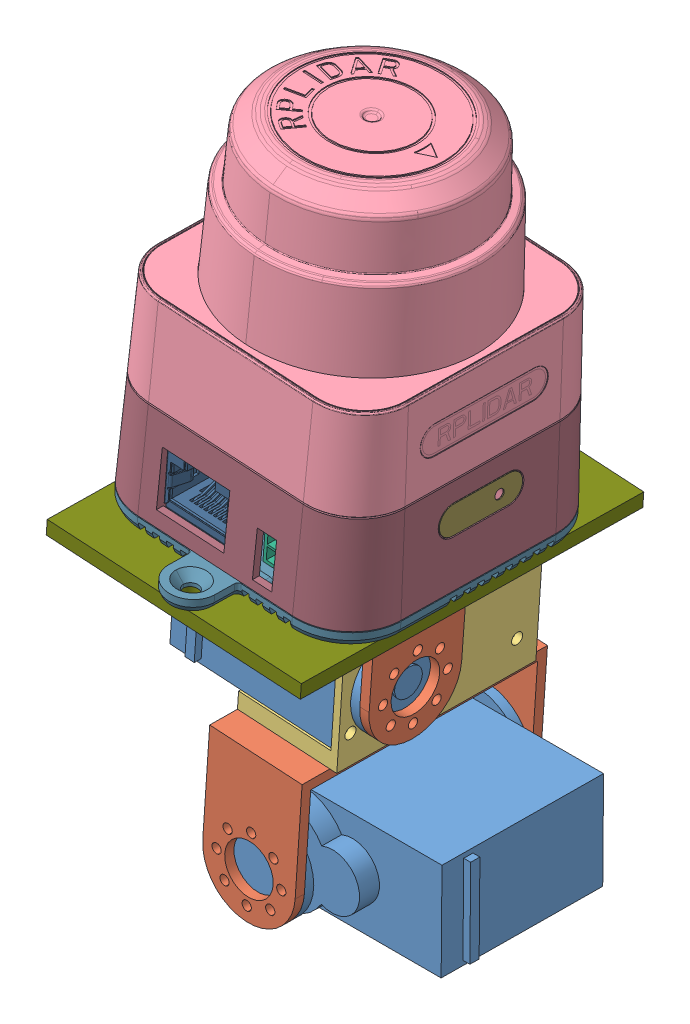
SolidWorks assembly SLAM_Platform, configuration 預設. Lengths in mm.
Overall size (113.01 151.02 98.42).
20 component instances, 16 part files, 32 mates.
Components (placement in the parent):
- KRS_786-1: KRS_786 [預設] at (-28.6478 -1.4384 68.5627) x (1 0 0) z (0 -0.008727 -0.999962) size (44 21 49.5)
- KRS_786-2: KRS_786 [預設] at (-61.3337 36.3416 52.8324) x (0 -0.008727 -0.999962) z (0.998231 -0.059451 0.000519) size (44 21 49.5)
- MotorRotate-1: MotorRotate [預設] at (-37.3398 20.3875 52.9716) x (0 -0.008727 -0.999962) z (-0.059453 -0.998193 0.008711) size (53 20 32)
- MotorRotate2-1: MotorRotate2 [預設] at (-37.3398 20.3875 52.9716) x (0.998231 -0.059451 0.000519) z (0.059453 0.998193 -0.008711) size (21.5 43 25)
- MotorRotate-2: MotorRotate [預設] at (-44.653 57.4718 62.5031) x (-0.998231 0.059451 -0.000519) z (-0.059452 -0.998114 0.015312) size (53 20 32)
- SLAMTEC MAPPER M2M1_IGS-1: SLAMTEC MAPPER M2M1_IGS [預設] at (-33.4707 83.7504 62.0962) x (-0.000392 -0.015316 -0.999883) z (-0.059452 -0.998114 0.015312) size (97.23 108.71 74.91)
  - SLAMTEC MAPPER M2M1_IGS(2)^SLAMTEC MAPPER M2M1_IGS-1: SLAMTEC MAPPER M2M1_IGS(2)^SLAMTEC MAPPER M2M1_IGS [預設] at origin size (97.23 108.71 74.91) (virtual)
    - rplidar-s1m1-r1^SLAMTEC MAPPER M2M1_IGS(2)_SLAMTEC MAPPER M2M1_IGS-1: rplidar-s1m1-r1^SLAMTEC MAPPER M2M1_IGS(2)_SLAMTEC MAPPER M2M1_IGS [預設] at origin size (97.23 108.71 51.5) (virtual)
    - 厙釐曹揤 ^SLAMTEC MAPPER M2M1_IGS(2)_SLAMTEC MAPPER M2M1_IGS-1: 厙釐曹揤 ^SLAMTEC MAPPER M2M1_IGS(2)_SLAMTEC MAPPER M2M1_IGS [預設] at (-6.25 -5.803 2.75) x (0 1 0) z (0 0 1) size (12.81 9.31 5.66) (virtual)
    - DC脣釱^SLAMTEC MAPPER M2M1_IGS(2)_SLAMTEC MAPPER M2M1_IGS-1: DC脣釱^SLAMTEC MAPPER M2M1_IGS(2)_SLAMTEC MAPPER M2M1_IGS [預設] at (-21.55 9.972 13.335) x (0 -1 0) z (-1 0 0) size (7.16 11.96 12.25) (virtual)
    - User Library-JST - SM06B-SRSS-TB (SH SERIES - 1_0mm PITCH WIRE-TO-BOARD, SMT, RA)^SLAMTEC MAPPER M2M1_IGS(2)_SLAMTEC MAPPER M2M1_IGS-1: User Library-JST - SM06B-SRSS-TB (SH SERIES - 1_0mm PITCH WIRE-TO-BOARD, SMT, RA)^SLAMTEC MAPPER M2M1_IGS(2)_SLAMTEC MAPPER M2M1_IGS [預設] at (0 -23.25 9.4) x (1 0 0) z (0 -1 0) size (8.81 3.31 4.96) (virtual)
    - User Library-JST - SM04B-SRSS-TB (SH SERIES - 1_0mm PITCH WIRE-TO-BOARD, SMT, RA)^SLAMTEC MAPPER M2M1_IGS(2)_SLAMTEC MAPPER M2M1_IGS-1: User Library-JST - SM04B-SRSS-TB (SH SERIES - 1_0mm PITCH WIRE-TO-BOARD, SMT, RA)^SLAMTEC MAPPER M2M1_IGS(2)_SLAMTEC MAPPER M2M1_IGS [預設] at (9.8 -23.25 9.4) x (1 0 0) z (0 -1 0) size (6.91 3.31 4.96) (virtual)
    - 綻蟯邧伎LED^SLAMTEC MAPPER M2M1_IGS(2)_SLAMTEC MAPPER M2M1_IGS-1: 綻蟯邧伎LED^SLAMTEC MAPPER M2M1_IGS(2)_SLAMTEC MAPPER M2M1_IGS [預設] at (-4 23.52 7.9) x (1 0 0) z (0 1 0) size (3.21 1.01 1.49) (virtual)
    - RJ45 1X1 SMT 8P8C-B脣釱 LCP窪遠悵__J17 DJ^SLAMTEC MAPPER M2M1_IGS(2)_SLAMTEC MAPPER M2M1_IGS-1: RJ45 1X1 SMT 8P8C-B脣釱 LCP窪遠悵__J17 DJ^SLAMTEC MAPPER M2M1_IGS(2)_SLAMTEC MAPPER M2M1_IGS [預設] at (-12.775 2.597 6.35) x (0 -1 0) z (0 0 -1) size (18.41 15.1 11.62) (virtual)
    - K2-1823SA葩弇羲壽^SLAMTEC MAPPER M2M1_IGS(2)_SLAMTEC MAPPER M2M1_IGS-1: K2-1823SA葩弇羲壽^SLAMTEC MAPPER M2M1_IGS(2)_SLAMTEC MAPPER M2M1_IGS [預設] at (4 23.75 7.1) x (-1 0 0) z (0 0 1) size (4.01 3.21 1.81) (virtual)
    - BAT_COVER1^SLAMTEC MAPPER M2M1_IGS(2)_SLAMTEC MAPPER M2M1_IGS-1: BAT_COVER1^SLAMTEC MAPPER M2M1_IGS(2)_SLAMTEC MAPPER M2M1_IGS [預設] at (0 -0.1187 -3.4) x (1 0 0) z (0 1 0) size (18.02 6.02 0.42) (virtual)
    - Mapper2-奻褲^SLAMTEC MAPPER M2M1_IGS(2)_SLAMTEC MAPPER M2M1_IGS-1: Mapper2-奻褲^SLAMTEC MAPPER M2M1_IGS(2)_SLAMTEC MAPPER M2M1_IGS [預設] x (1 0 0) z (0 1 0) size (57.05 23.13 57.05) (virtual)
    - MP2-底板-1031^SLAMTEC MAPPER M2M1_IGS(2)_SLAMTEC MAPPER M2M1_IGS-1: MP2-底板-1031^SLAMTEC MAPPER M2M1_IGS(2)_SLAMTEC MAPPER M2M1_IGS [預設] at (0 0 -1.6) x (1 0 0) z (0 1 0) size (77.12 5.51 57) (virtual)
    - Thermal pad_pad^SLAMTEC MAPPER M2M1_IGS(2)_SLAMTEC MAPPER M2M1_IGS-1: Thermal pad_pad^SLAMTEC MAPPER M2M1_IGS(2)_SLAMTEC MAPPER M2M1_IGS [預設] at (2 2.4517 21.4) x (-1 0 0) z (0 1 0) size (24.01 1.76 15.01) (virtual)
- M2M1_base-1: M2M1_base [預設] at (-34.9915 59.9014 62.4621) x (0.000392 0.015316 0.999883) z (-0.059452 -0.998114 0.015312) size (74 55 3)
Mates (geometry in assembly coordinates):
- 重合/共線/共點1: coincident: plane of KRS_786-1 through (-38.6478 -1.359 77.6623) normal (0 0.008727 0.999962); plane of MotorRotate-1 through (-29.26 -11.9354 77.7546) normal (0 -0.008727 -0.999962)
- 同軸心1: concentric: circle of KRS_786-1; circle of MotorRotate-1
- 重合/共線/共點2: coincident: plane of MotorRotate-1 through (-37.3398 20.3875 52.9716) normal (0.059453 0.998193 -0.008711); plane of MotorRotate2-1 through (-37.3398 20.3875 52.9716) normal (-0.059453 -0.998193 0.008711)
- 同軸心2: concentric: circle of MotorRotate-1; circle of MotorRotate2-1
- 同軸心3: concentric: circle of MotorRotate-1; circle of MotorRotate2-1
- 重合/共線/共點6: coincident: plane of KRS_786-2 through (-26.4955 34.2668 52.8505) normal (0.998231 -0.059451 0.000519); plane of MotorRotate2-1 through (-25.8712 44.7478 52.759) normal (-0.998231 0.059451 -0.000519)
- 同軸心4: concentric: cylinder of KRS_786-2 through (-36.0021 43.0039 70.7749) axis (0.998231 -0.059451 0.000519) radius 1; cylinder of MotorRotate2-1 through (-45.9844 43.5984 70.7698) axis (0.998231 -0.059451 0.000519) radius 1.2
- 同軸心5: concentric: cylinder of KRS_786-2 through (-36.9534 26.7187 34.9157) axis (0.998231 -0.059451 0.000519) radius 1; cylinder of MotorRotate2-1 through (-46.9357 27.3132 34.9105) axis (0.998231 -0.059451 0.000519) radius 1.2
- 重合/共線/共點8: coincident: plane of KRS_786-2 through (-70.4176 36.9699 62.8273) normal (-0.998231 0.059451 -0.000519); plane of MotorRotate-2 through (-71.0161 26.8356 52.9816) normal (0.998231 -0.059451 0.000519)
- 同軸心6: concentric: cylinder of KRS_786-2 through (-70.4176 36.9699 62.8273) axis (0.998231 -0.059451 0.000519) radius 10; cylinder of MotorRotate-2 through (-19.5068 33.9378 62.8538) axis (-0.998231 0.059451 -0.000519) radius 5.25
- 重合/共線/共點9: coincident: plane of MotorRotate-2 through (-44.653 57.4718 62.5031) normal (0.059452 0.998114 -0.015312); plane of M2M1_base-1 through (-35.1698 56.907 62.5081) normal (-0.059452 -0.998114 0.015312)
- 同軸心14: concentric: circle of SLAMTEC MAPPER M2M1_IGS-1/SLAMTEC MAPPER M2M1_IGS(2)^SLAMTEC MAPPER M2M1_IGS-1/rplidar-s1m1-r1^SLAMTEC MAPPER M2M1_IGS(2)_SLAMTEC MAPPER M2M1_IGS-1; circle of M2M1_base-1
- 同軸心15: concentric: circle of SLAMTEC MAPPER M2M1_IGS-1/SLAMTEC MAPPER M2M1_IGS(2)^SLAMTEC MAPPER M2M1_IGS-1/rplidar-s1m1-r1^SLAMTEC MAPPER M2M1_IGS(2)_SLAMTEC MAPPER M2M1_IGS-1; circle of M2M1_base-1
- 重合/共線/共點14: coincident: line of SLAMTEC MAPPER M2M1_IGS-1/SLAMTEC MAPPER M2M1_IGS(2)^SLAMTEC MAPPER M2M1_IGS-1/rplidar-s1m1-r1^SLAMTEC MAPPER M2M1_IGS(2)_SLAMTEC MAPPER M2M1_IGS-1 through (-34.9048 59.3815 28.9129) axis (0.000392 0.015316 0.999883); plane of M2M1_base-1 through (-34.9915 59.9014 62.4621) normal (0.059452 0.998114 -0.015312)
- 同軸心16: concentric: cylinder of MotorRotate-2 through (-39.5679 25.116 62.9968) axis (0.059452 0.998114 -0.015312) radius 1.3; cylinder of M2M1_base-1 through (-37.487 60.05 62.4608) axis (-0.059452 -0.998114 0.015312) radius 1.3
- 同軸心17: concentric: cylinder of MotorRotate-2 through (-53.5431 25.9483 62.9895) axis (0.059452 0.998114 -0.015312) radius 1.3; cylinder of M2M1_base-1 through (-51.4623 60.8823 62.4536) axis (-0.059452 -0.998114 0.015312) radius 1.3
- 重合/共線/共點17: coincident: plane of ? through (-125.7552 -8.8473 174.9239) normal (0 -0.008727 -0.999962); plane of ? through (-135.7877 1.1196 174.837) normal (0 0.008727 0.999962)
- 重合/共線/共點18: coincident: plane of ? through (-169.874 27.2944 150.1069) normal (0.999995 0.003262 -0.000028); plane of ? through (-169.9066 37.3806 160.02) normal (-0.999995 -0.003262 0.000028)
- 重合/共線/共點19: coincident: plane of ? through (-135.8595 22.9049 150.1459) normal (0.003263 -0.999957 0.008726); plane of ? through (-135.8595 22.9049 150.1459) normal (-0.003263 0.999957 -0.008726)
- 重合/共線/共點20: coincident: plane of ? through (-125.9411 47.9364 149.9275) normal (-0.999995 -0.003262 0.000028); plane of ? through (-125.9069 37.4368 150.0191) normal (0.999995 0.003262 -0.000028)
- 同軸心18: concentric: circle of ?; circle of ?
- 同軸心19: concentric: cylinder of ? through (-145.9329 45.5283 167.9492) axis (0.999995 0.003262 -0.000028) radius 1.2; cylinder of ? through (-135.9329 45.561 167.9489) axis (0.999995 0.003262 -0.000028) radius 1
- 同軸心20: concentric: circle of ?; circle of ?
- 同軸心21: concentric: circle of ?; circle of ?
- 同軸心25: concentric: cylinder of ? through (-145.8807 29.2149 132.0902) axis (0.999995 0.003262 -0.000028) radius 1.2; cylinder of ? through (-135.8807 29.2475 132.0899) axis (0.999995 0.003262 -0.000028) radius 1
- 同軸心27: concentric: cylinder of ? through (-118.9059 37.547 160.0185) axis (-0.999995 -0.003262 0.000028) radius 5.25; cylinder of ? through (-169.9066 37.3806 160.02) axis (0.999995 0.003262 -0.000028) radius 10
- 重合/共線/共點21: coincident: plane of ? through (-135.9786 59.4905 159.8285) normal (0.003263 -0.999957 0.008657); plane of ? through (-145.4786 59.4596 159.8288) normal (-0.003263 0.999957 -0.008657)
- 同軸心28: concentric: cylinder of ? through (-152.4883 62.4366 159.803) axis (0.003263 -0.999957 0.008657) radius 1.3; cylinder of ? through (-152.3741 27.4381 160.106) axis (-0.003263 0.999957 -0.008657) radius 1.3
- 同軸心29: concentric: cylinder of ? through (-138.4884 62.4823 159.8026) axis (0.003263 -0.999957 0.008657) radius 1.3; cylinder of ? through (-138.3742 27.4838 160.1056) axis (-0.003263 0.999957 -0.008657) radius 1.3
- 同軸心30: concentric: cylinder of ? through (-112.9885 62.5655 159.8019) axis (0.003263 -0.999957 0.008657) radius 1.6; circle of ?
- 重合/共線/共點22: coincident: plane of ? through (-135.9884 62.4904 159.8026) normal (-0.003263 0.999957 -0.008657); line of ? through (-169.5414 62.381 159.8035) axis (0.999995 0.003262 -0.000028)
- 同軸心31: concentric: cylinder of ? through (-158.9883 62.4154 159.8032) axis (0.003263 -0.999957 0.008657) radius 1.6; circle of ?
